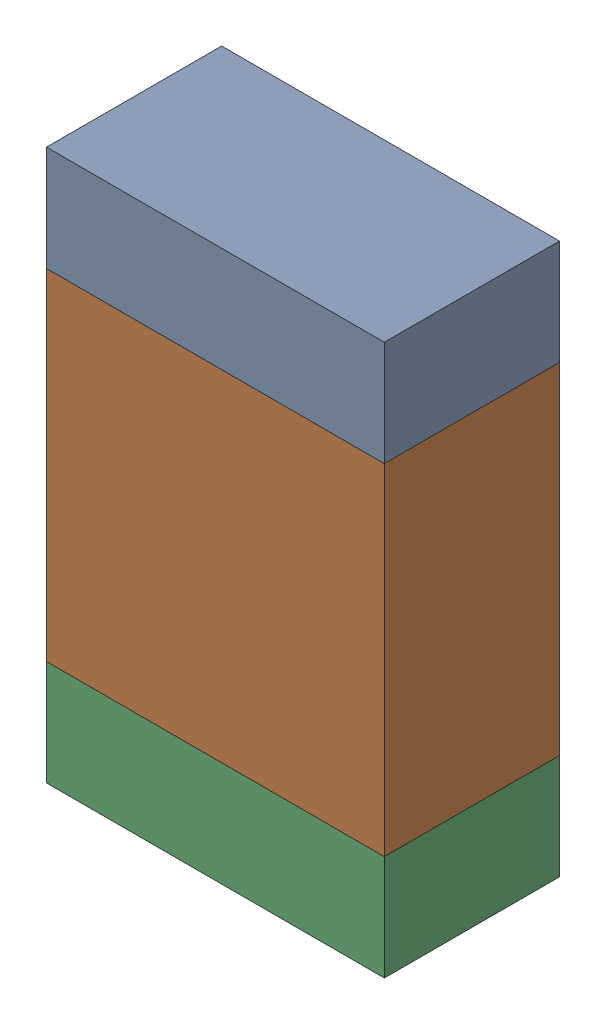
SolidWorks assembly R3, configuration Default. Lengths in mm.
Overall size (1.35 2.2 0.7).
6 component instances, 2 part files, 0 mates.
Components (placement in the parent):
- 959207304-1: 959207304 [Default] at (114.1729 78.1061 0) size (1.35 0.42 0.7)
  - Extruded-8-1: Extruded-8 [Default] at origin size (1.35 0.42 0.7)
- 959207440-1: 959207440 [Default] at (114.1729 77.2161 0) size (1.35 1.36 0.7)
  - Extruded-9-1: Extruded-9 [Default] at origin size (1.35 1.36 0.7)
- 959207304-2: 959207304 [Default] at (114.1729 76.3261 0) size (1.35 0.42 0.7)
  - Extruded-8-1: Extruded-8 [Default] at origin size (1.35 0.42 0.7)
